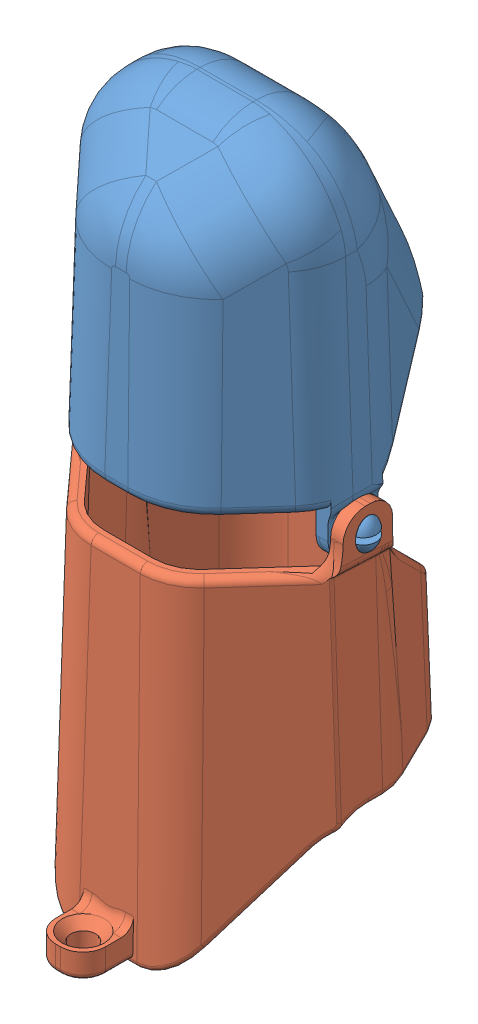
SolidWorks assembly finger_thumb, configuration Default. Lengths in mm.
Overall size (29.61 70.57 30.21).
2 component instances, 2 part files, 2 mates.
Components (placement in the parent):
- thumb_distal-1: thumb_distal [Default] at (-16.8122 -43.7943 -8.7589) size (29.61 35.57 23.38)
- thumb_proximal-1: thumb_proximal [Default] at (-15.4493 -10.7743 -7.8979) size (28.04 40.09 30.21)
Mates (geometry in assembly coordinates):
- Concentric1: concentric anti-aligned: circle of thumb_proximal-1; circle of thumb_distal-1
- Distance1: distance = 0.254 mm anti-aligned: plane of thumb_distal-1 through (9.5742 10.8157 11.7897) normal (1 0 0); plane of thumb_proximal-1 through (9.8282 15.8957 16.0196) normal (-1 0 0)
